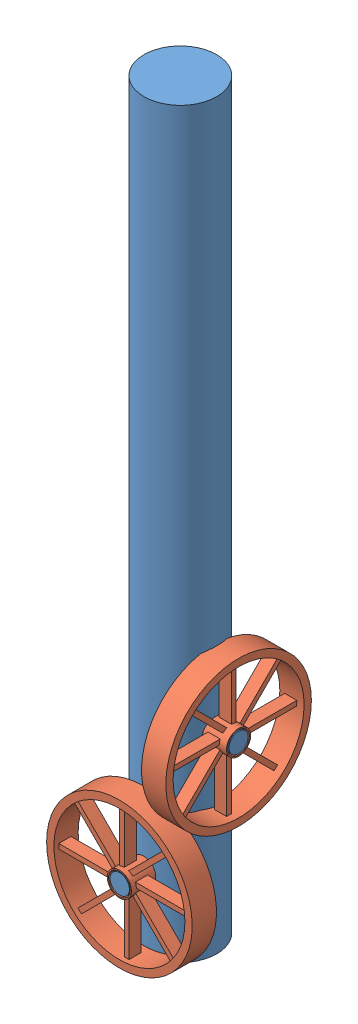
SolidWorks assembly GyroScope, configuration Default. Lengths in mm.
Overall size (60 115.04 60).
3 component instances, 2 part files, 3 mates.
Components (placement in the parent):
- gyro-1: gyro [Default] at (126.3891 49.8515 303.0815) size (39 115.04 40)
- flywheel-1: flywheel [Default] at (126.3891 79.8515 318.2042) size (60 60 10)
- flywheel-2: flywheel [Default] at (150.3891 129.8515 303.0815) x (0 0 1) z (-1 0 0) size (60 60 10)
Mates (geometry in assembly coordinates):
- Concentric1: concentric aligned: circle of gyro-1; circle of flywheel-1
- Concentric2: concentric anti-aligned: circle of gyro-1; circle of flywheel-2
- Coincident1: coincident aligned: plane of gyro-1 through (150.3891 129.8515 303.0815) normal (1 0 0); plane of flywheel-2 through (150.3891 129.8515 303.0815) normal (1 0 0)
